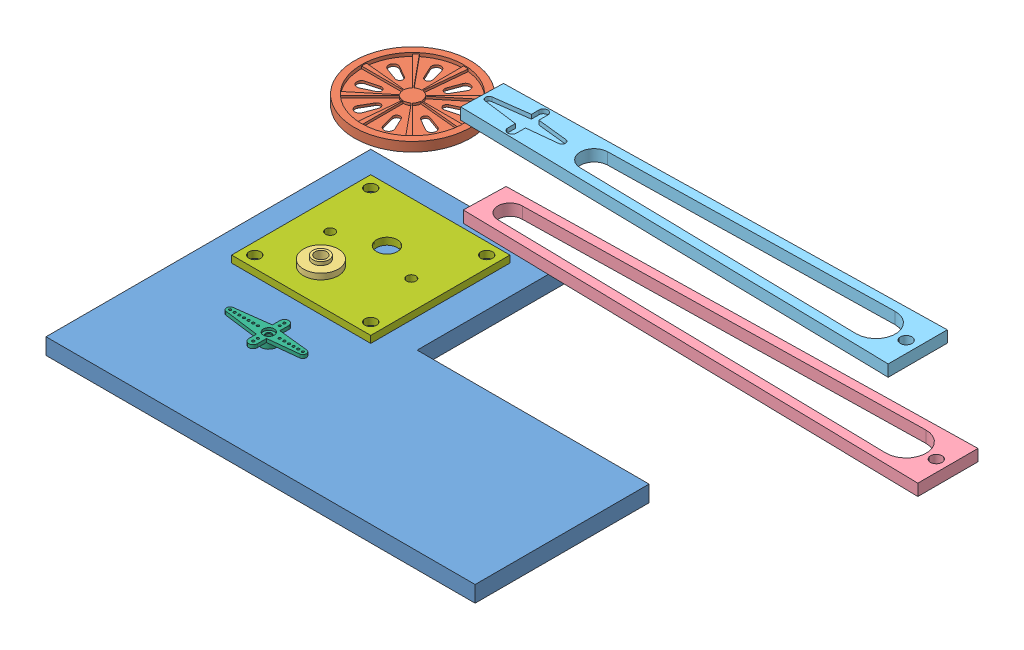
SolidWorks assembly Assem2, configuration Default. Lengths in mm.
Overall size (296.55 67.58 168.79).
7 component instances, 7 part files, 3 mates.
Components (placement in the parent):
- Lower base-1: Lower base [Default] at origin size (185 7 140)
- Circular base-1: Circular base [Default] at (-56.4676 30.7972 -35.6883) size (50 4 50)
- Elbow-1: Elbow [Default] at (-25.1328 19.8104 35.1505) size (15 4 15)
- Arm 2 (lebih panjang)-1: Arm 2 (lebih panjang) [Default] at (105.5663 45.1799 -46.0148) size (200 5 25.96)
- Arm 1 (lebih pendek)-1: Arm 1 (lebih pendek) [Default] at (83.9357 62.5765 -66.5162) size (188.12 5 25.49)
- meArmUPV_Tower pro micro servo SG90 HORN-1: meArmUPV_Tower pro micro servo SG90 HORN [Varsayılan] at (-18.4115 11.5 64.3299) size (34.4 4 17.3)
- Upper base-1: Upper base [Default] at (-28.1817 7 10.6051) size (60 3 60)
Mates (geometry in assembly coordinates):
- Concentric1: concentric: cylinder of Lower base-1 through (-3.1817 4 35.6051) axis (0 1 0) radius 2.5; cylinder of Upper base-1 through (-3.1817 10 35.6051) axis (0 -1 0) radius 2.5
- Coincident1: coincident: plane of Lower base-1 through (0 7 0) normal (0 1 0); plane of Upper base-1 through (-28.1817 7 10.6051) normal (0 -1 0)
- Parallel1: parallel aligned: plane of Lower base-1 through (14.3183 7 -31.8949) normal (0 0 -1); plane of Upper base-1 through (-28.1817 10 -19.3949) normal (0 0 -1)
